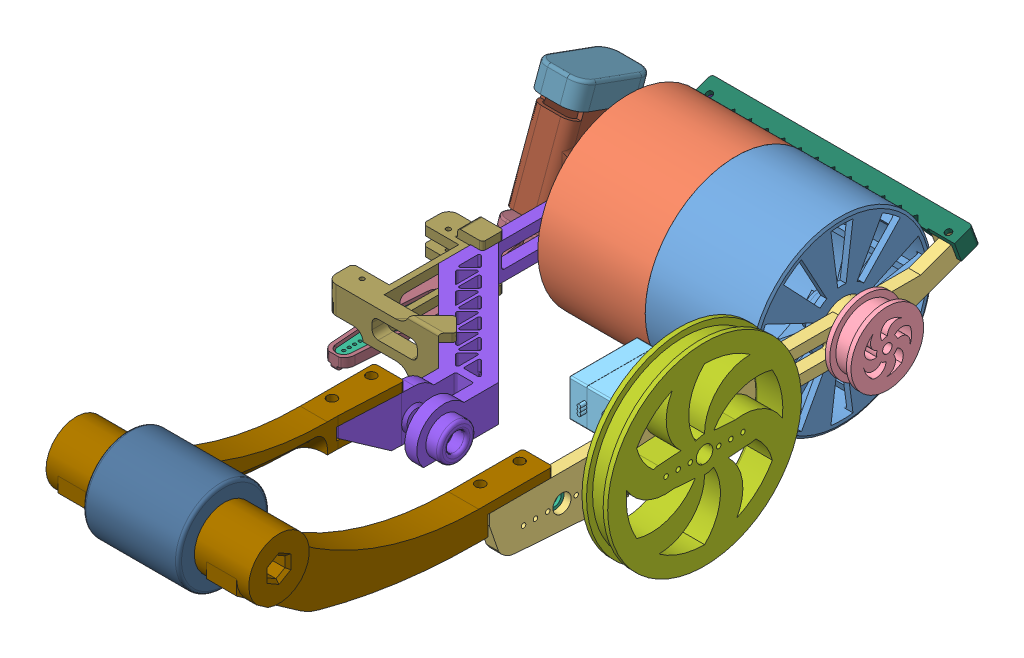
SolidWorks assembly _COLLECTOR, configuration Default. Lengths in mm.
Overall size (113.4 64.05 160.33).
23 component instances, 15 part files, 55 mates.
Components (placement in the parent):
- Copy of cylinder_1^_COLLECTOR-1: Copy of cylinder_1^_COLLECTOR [Default] x (0 0 -1) z (1 0 0) size (60 60 43) (virtual)
- cylinder_2^_COLLECTOR-1: cylinder_2^_COLLECTOR [Default] x (0 0 1) z (-1 0 0) size (60 60 36) (virtual)
- Part6^_COLLECTOR-1: Part6^_COLLECTOR [Default] at (35.5 0 0) x (0 0 -1) z (1 0 0) size (158.85 20.18 10.7) (virtual)
- Part7^_COLLECTOR-1: Part7^_COLLECTOR [Default] at (40.5 0 0) x (0 0 -1) z (1 0 0) size (24 24 10.5) (virtual)
- microservoAssembly-1: microservoAssembly [Default] at (8.2345 26 63.1094) x (0 0 -1) z (0 -1 0) size (38.45 31.3 12.5)
  - microservoSG90-1: microservoSG90 [Default] at (7.8094 3.3655 26.0766) size (32.3 29.8 12.5) (hidden)
  - microservoArm-1: microservoArm [A2] at (2.7094 34.6655 26.0766) x (-1 0 0.000751) z (0.000751 0 1) size (34.4 3.9 7)
- Part8^_COLLECTOR-1: Part8^_COLLECTOR [Default] at (42.9 -0.0766 60.4) x (0 0.000751 -1) z (1 0 0) size (64 64 9.5) (virtual)
- microservoAssembly-2: microservoAssembly [Default] at (3.2345 26 100.7094) x (0 0 -1) z (0 -1 0) size (38.45 31.3 12.5)
  - microservoSG90-1: microservoSG90 [Default] at (7.8094 3.3655 26.0766) size (32.3 29.8 12.5) (hidden)
  - microservoArm-1: microservoArm [A2] at (2.7094 34.6655 26.0766) x (-1 0 0.000751) z (0.000751 0 1) size (34.4 3.9 7)
- Part11^_COLLECTOR-1: Part11^_COLLECTOR [Default] at (-36.5 0 0) x (0 0 1) z (-1 0 0) size (158.85 17.18 48.5) (virtual)
- Part19^_COLLECTOR-1: Part19^_COLLECTOR [Default] at (35.5 9 0) x (0 0 -1) z (0 1 0) size (104.5 67 39.5) (hidden, virtual)
- Part20^_COLLECTOR-1: Part20^_COLLECTOR [Default] at (26.3 0 0) x (0 0 1) z (-1 0 0) size (30 30 31.6) (hidden, virtual)
- bag-1: bag [Default] at (-54.95 -11.5 0.05) x (0 0 1) z (-1 0 0) size (30.85 40.59 23.5)
- opener-1: opener [Default] at (-24.6234 21.7655 66.4094) x (0 0 -1) z (-1 0 0) size (88.8 39.31 46.4)
  - microservoAssembly-1: microservoAssembly [Default] at origin size (38.45 31.3 12.5)
    - microservoSG90-1: microservoSG90 [Default] at (7.8094 3.3655 26.0766) size (32.3 29.8 12.5) (hidden)
    - microservoArm-1: microservoArm [A2] at (2.7094 34.6655 26.0766) x (-1 0 0.000751) z (0.000751 0 1) size (34.4 3.9 7)
  - Part5^opener-1: Part5^opener [Default] at (66.4094 21.7655 17.8766) x (-1 0 0) z (0 0 1) size (40.3 18 39.51) (virtual)
  - Part6^opener-1: Part6^opener [Default] at (2.7094 34.6655 26.0766) x (1 0 -0.000751) z (0 1 0) size (88.79 18.43 12.34) (virtual)
- Part3^_COLLECTOR-1: Part3^_COLLECTOR [Default] at (-54.95 22.5036 -12.3263) x (0 0.34202 0.939693) z (0 0.939693 -0.34202) size (25.7 16.2 8) (virtual)
- Part9^_COLLECTOR-1: Part9^_COLLECTOR [Default] at (35.5 -1.2914 -0.47) x (0 0.34202 -0.939693) z (0 0.939693 0.34202) size (6.97 86.4 6.5) (virtual)
Mates (geometry in assembly coordinates):
- InPlace1: in place: plane of Copy of cylinder_1^_COLLECTOR-1 through (0 0 0) normal (1 0 0); moOrthogonalPlaneRef_w of Copy of cylinder_1^_COLLECTOR-1 through (0 0 0) normal (0 1 0); plane of Copy of cylinder_1^_COLLECTOR-1 through (0 0 0) normal (0 0 -1); unknown of Copy of cylinder_1^_COLLECTOR-1
- Coincident1: coincident aligned: 
- Coincident2: coincident aligned: plane of Copy of cylinder_1^_COLLECTOR-1 through (0 0 0) normal (0 1 0)
- Coincident3: coincident anti-aligned: plane of Copy of cylinder_1^_COLLECTOR-1 through (0 0 0) normal (0 0 -1)
- InPlace2: in place: plane of Copy of cylinder_1^_COLLECTOR-1 through (0 0 0) normal (-1 0 0); plane of cylinder_2^_COLLECTOR-1 through (0 0 0) normal (-1 0 0); plane of Copy of cylinder_1^_COLLECTOR-1 through (0 0 0) normal (-1 0 0); plane of cylinder_2^_COLLECTOR-1 through (0 0 0) normal (0 1 0); plane of Copy of cylinder_1^_COLLECTOR-1 through (0 0 0) normal (-1 0 0); plane of cylinder_2^_COLLECTOR-1 through (0 0 0) normal (0 0 1); plane of Copy of cylinder_1^_COLLECTOR-1 through (0 0 0) normal (-1 0 0); unknown of cylinder_2^_COLLECTOR-1
- Coincident4: coincident aligned: plane of Copy of cylinder_1^_COLLECTOR-1; plane of cylinder_2^_COLLECTOR-1
- Coincident5: coincident aligned: moOrthogonalPlaneRef_w of Copy of cylinder_1^_COLLECTOR-1 through (0 0 0) normal (0 1 0); plane of cylinder_2^_COLLECTOR-1 through (0 0 0) normal (0 1 0)
- Coincident6: coincident anti-aligned: moOrthogonalPlaneRef_w of Copy of cylinder_1^_COLLECTOR-1 through (0 0 0) normal (0 0 -1); plane of cylinder_2^_COLLECTOR-1 through (0 0 0) normal (0 0 1)
- InPlace4: in place: plane of Part6^_COLLECTOR-1 through (35.5 0 0) normal (1 0 0); plane of Part6^_COLLECTOR-1 through (35.5 0 0) normal (0 1 0); plane of Part6^_COLLECTOR-1 through (35.5 0 0) normal (0 0 -1); unknown of Part6^_COLLECTOR-1
- Coincident10: coincident aligned: 
- Coincident11: coincident aligned: plane of Part6^_COLLECTOR-1 through (35.5 0 0) normal (0 1 0)
- Coincident12: coincident anti-aligned: plane of Part6^_COLLECTOR-1 through (35.5 0 0) normal (0 0 -1)
- InPlace5: in place: plane of Part6^_COLLECTOR-1 through (40.5 0 0) normal (1 0 0); plane of Part7^_COLLECTOR-1 through (40.5 0 0) normal (1 0 0); plane of Part6^_COLLECTOR-1 through (40.5 0 0) normal (1 0 0); plane of Part7^_COLLECTOR-1 through (40.5 0 0) normal (0 1 0); plane of Part6^_COLLECTOR-1 through (40.5 0 0) normal (1 0 0); plane of Part7^_COLLECTOR-1 through (40.5 0 0) normal (0 0 -1); plane of Part6^_COLLECTOR-1 through (40.5 0 0) normal (1 0 0); unknown of Part7^_COLLECTOR-1
- Coincident13: coincident aligned: plane of Part6^_COLLECTOR-1; plane of Part7^_COLLECTOR-1
- Coincident14: coincident aligned: moOrthogonalPlaneRef_w of Part6^_COLLECTOR-1 through (40.5 0 0) normal (0 1 0); plane of Part7^_COLLECTOR-1 through (40.5 0 0) normal (0 1 0)
- Coincident15: coincident anti-aligned: moOrthogonalPlaneRef_w of Part6^_COLLECTOR-1 through (40.5 0 0) normal (0 0 1); plane of Part7^_COLLECTOR-1 through (40.5 0 0) normal (0 0 -1)
- Coincident16: coincident aligned: plane of Part7^_COLLECTOR-1 through (41.5 0 0) normal (-1 0 0); plane of microservoAssembly-1/microservoArm-1 through (41.5 -0.0652 45.2) normal (-1 0 0)
- Parallel1: parallel aligned: plane of Part6^_COLLECTOR-1 through (40.5 6 0) normal (0 1 0); plane of microservoAssembly-1/microservoSG90-1 through (27.2 6.1234 66.6) normal (0 1 0)
- Distance1: distance = 26 mm: plane of assembly through (0 0 0) normal (0 1 0); plane of assembly; plane of microservoAssembly-1 through (8.2345 26 63.1094) normal (0 -1 0)
- Distance2: distance = 44 mm: plane of assembly through (0 0 0) normal (0 0 1); plane of assembly; plane of microservoAssembly-1/microservoSG90-1 through (27.2 -6.2766 44) normal (0 0 -1)
- InPlace6: in place: plane of microservoAssembly-1/microservoArm-1 through (42.9 -0.0652 45.2) normal (1 0 0); plane of ? through (42.9 0 0) normal (1 0 0); plane of microservoAssembly-1/microservoArm-1 through (42.9 -0.0652 45.2) normal (1 0 0); plane of ? through (42.9 0 0) normal (0 1 0); plane of microservoAssembly-1/microservoArm-1 through (42.9 -0.0652 45.2) normal (1 0 0); plane of ? through (42.9 0 0) normal (0 0 -1); plane of microservoAssembly-1/microservoArm-1 through (42.9 -0.0652 45.2) normal (1 0 0); unknown of Part8^_COLLECTOR-1
- Coincident21: coincident aligned: plane of microservoAssembly-1/microservoArm-1; plane of Part8^_COLLECTOR-1
- Coincident22: coincident aligned: moOrthogonalPlaneRef_w of microservoAssembly-1/microservoArm-1 through (42.9 -0.0766 60.4) normal (0 1 0.000751); plane of Part8^_COLLECTOR-1 through (42.9 -0.0766 60.4) normal (0 1 0.000751)
- Coincident23: coincident anti-aligned: moOrthogonalPlaneRef_w of microservoAssembly-1/microservoArm-1 through (42.9 -0.0766 60.4) normal (0 -0.000751 1); plane of Part8^_COLLECTOR-1 through (42.9 -0.0766 60.4) normal (0 0.000751 -1)
- Coincident24: coincident aligned: plane of Part6^_COLLECTOR-1 through (36.5 0 0) normal (-1 0 0); plane of microservoAssembly-2/microservoArm-1 through (36.5 -0.0652 82.8) normal (-1 0 0)
- Coincident25: coincident aligned: plane of microservoAssembly-1/microservoSG90-1 through (27.2 6.1234 66.6) normal (0 1 0); plane of microservoAssembly-2/microservoSG90-1 through (22.2 6.1234 104.2) normal (0 1 0)
- Distance3: distance = 15 mm anti-aligned: plane of microservoAssembly-1/microservoSG90-1 through (27.2 -6.2766 66.6) normal (0 0 1); plane of microservoAssembly-2/microservoSG90-1 through (22.2 -6.2766 81.6) normal (0 0 -1)
- InPlace7: in place: plane of Part11^_COLLECTOR-1 through (-36.5 0 0) normal (-1 0 0); plane of Part11^_COLLECTOR-1 through (-36.5 0 0) normal (0 1 0); plane of Part11^_COLLECTOR-1 through (-36.5 0 0) normal (0 0 1); unknown of Part11^_COLLECTOR-1
- Coincident27: coincident aligned: 
- Coincident28: coincident aligned: plane of Part11^_COLLECTOR-1 through (-36.5 0 0) normal (0 1 0)
- Coincident29: coincident anti-aligned: plane of Part11^_COLLECTOR-1 through (-36.5 0 0) normal (0 0 1)
- InPlace8: in place: plane of Part6^_COLLECTOR-1 through (-16.6413 9 80) normal (0 1 0); plane of ? through (0 9 0) normal (0 1 0); plane of Part6^_COLLECTOR-1 through (-16.6413 9 80) normal (0 1 0); plane of ? through (0 9 0) normal (0 0 -1); plane of Part6^_COLLECTOR-1 through (-16.6413 9 80) normal (0 1 0); plane of ? through (0 9 0) normal (1 0 0); plane of Part6^_COLLECTOR-1 through (-16.6413 9 80) normal (0 1 0); unknown of Part19^_COLLECTOR-1
- Coincident26: coincident aligned: plane of Part6^_COLLECTOR-1; plane of Part19^_COLLECTOR-1
- Coincident27: coincident aligned: moOrthogonalPlaneRef_w of Part6^_COLLECTOR-1 through (35.5 9 0) normal (-1 0 0); plane of Part19^_COLLECTOR-1 through (35.5 9 0) normal (-1 0 0)
- Coincident28: coincident anti-aligned: moOrthogonalPlaneRef_w of Part6^_COLLECTOR-1 through (35.5 9 0) normal (0 0 1); plane of Part19^_COLLECTOR-1 through (35.5 9 0) normal (0 0 -1)
- InPlace9: in place: plane of Part20^_COLLECTOR-1 through (26.3 0 0) normal (-1 0 0); plane of Part20^_COLLECTOR-1 through (26.3 0 0) normal (0 1 0); plane of Part20^_COLLECTOR-1 through (26.3 0 0) normal (0 0 1); unknown of Part20^_COLLECTOR-1
- Coincident29: coincident aligned: 
- Coincident30: coincident aligned: plane of Part20^_COLLECTOR-1 through (26.3 0 0) normal (0 1 0)
- Coincident31: coincident anti-aligned: plane of Part20^_COLLECTOR-1 through (26.3 0 0) normal (0 0 1)
- Coincident26: coincident anti-aligned: plane of Part11^_COLLECTOR-1 through (-42.5 0 0) normal (-1 0 0); plane of bag-1 through (-42.5 -11.5 0.05) normal (1 0 0)
- Coincident27: coincident anti-aligned: plane of Part11^_COLLECTOR-1 through (-41.5 6 0) normal (0 1 0); plane of bag-1 through (-42.5 6 7.3) normal (0 -1 0)
- Distance4: distance = 31.7 mm anti-aligned: plane of bag-1 through (-38.2 8.5 7.3) normal (0 0 1); plane of Part11^_COLLECTOR-1 through (-36.5 0 39) normal (0 0 -1)
- Parallel2: parallel anti-aligned: plane of opener-1/microservoAssembly-1/microservoSG90-1 through (-56.9 2.8 47.3) normal (0 0 -1); plane of bag-1 through (-38.2 8.5 7.3) normal (0 0 1)
- Parallel3: parallel aligned: plane of opener-1/microservoAssembly-1/microservoSG90-1 through (-54.85 -3.7 49.1) normal (0 -1 0); plane of bag-1 through (-38.2 -9.5 7.3) normal (0 -1 0)
- Distance5: distance = 2 mm anti-aligned: plane of opener-1/microservoAssembly-1/microservoArm-1 through (-50.6886 -11.5 48.5) normal (0 1 0); plane of bag-1 through (-38.2 -9.5 7.3) normal (0 -1 0)
- Distance6: distance = 2 mm anti-aligned: plane of opener-1/microservoAssembly-1/microservoSG90-1 through (-44.5 2.8 69.9) normal (1 0 0); plane of Part11^_COLLECTOR-1 through (-42.5 0 0) normal (-1 0 0)
- Distance7: distance = 40 mm anti-aligned: plane of bag-1 through (-38.2 8.5 7.3) normal (0 0 1); plane of opener-1/microservoAssembly-1/microservoSG90-1 through (-56.9 2.8 47.3) normal (0 0 -1)
- InPlace10: in place: plane of bag-1 through (-54.95 22.5036 -12.3263) normal (0 0.939693 -0.34202); plane of ? through (0 23.8328 -8.6744) normal (0 0.939693 -0.34202); plane of bag-1 through (-54.95 22.5036 -12.3263) normal (0 0.939693 -0.34202); plane of ? through (0 23.8328 -8.6744) normal (0 -0.34202 -0.939693); plane of bag-1 through (-54.95 22.5036 -12.3263) normal (0 0.939693 -0.34202); plane of ? through (0 23.8328 -8.6744) normal (1 0 0); plane of bag-1 through (-54.95 22.5036 -12.3263) normal (0 0.939693 -0.34202); unknown of Part3^_COLLECTOR-1
- Coincident31: coincident aligned: plane of bag-1; plane of Part3^_COLLECTOR-1
- Coincident32: coincident aligned: moOrthogonalPlaneRef_w of bag-1 through (-54.95 22.5036 -12.3263) normal (1 0 0); plane of Part3^_COLLECTOR-1 through (-54.95 22.5036 -12.3263) normal (1 0 0)
- Coincident33: coincident anti-aligned: moOrthogonalPlaneRef_w of bag-1 through (-54.95 22.5036 -12.3263) normal (0 -0.34202 -0.939693); plane of Part3^_COLLECTOR-1 through (-54.95 22.5036 -12.3263) normal (0 0.34202 0.939693)
- InPlace11: in place: plane of Part6^_COLLECTOR-1 through (29.8 11.1805 -34.7363) normal (0 0.939693 0.34202); plane of ? through (0 -1.2914 -0.47) normal (0 0.939693 0.34202); plane of Part6^_COLLECTOR-1 through (29.8 11.1805 -34.7363) normal (0 0.939693 0.34202); plane of ? through (0 -1.2914 -0.47) normal (0 0.34202 -0.939693); plane of Part6^_COLLECTOR-1 through (29.8 11.1805 -34.7363) normal (0 0.939693 0.34202); plane of ? through (0 -1.2914 -0.47) normal (1 0 0); plane of Part6^_COLLECTOR-1 through (29.8 11.1805 -34.7363) normal (0 0.939693 0.34202); unknown of Part9^_COLLECTOR-1
- Coincident34: coincident aligned: plane of Part6^_COLLECTOR-1; plane of Part9^_COLLECTOR-1
- Coincident35: coincident aligned: moOrthogonalPlaneRef_w of Part6^_COLLECTOR-1 through (35.5 -1.2914 -0.47) normal (-1 0 0); plane of Part9^_COLLECTOR-1 through (35.5 -1.2914 -0.47) normal (-1 0 0)
- Coincident36: coincident anti-aligned: moOrthogonalPlaneRef_w of Part6^_COLLECTOR-1 through (35.5 -1.2914 -0.47) normal (0 -0.34202 0.939693); plane of Part9^_COLLECTOR-1 through (35.5 -1.2914 -0.47) normal (0 0.34202 -0.939693)
